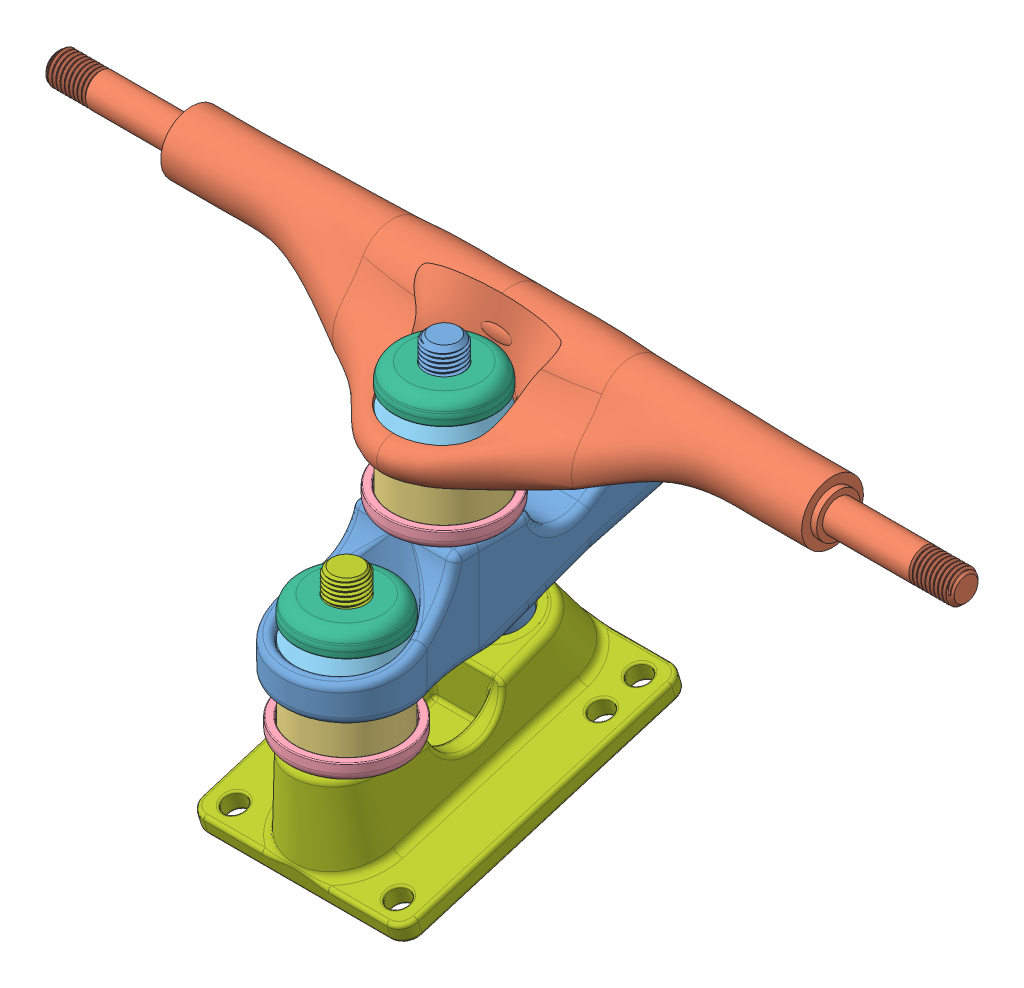
SolidWorks assembly sidewinder2_and_wheels_assembly, configuration Default. Lengths in mm.
Overall size (228 105.1 109.02).
13 component instances, 8 part files, 23 mates.
Components (placement in the parent):
- rocker-1: rocker [Default] at (-7.4415 -24.5069 31.8829) size (32.42 73.55 94.86)
- hanger_assembly-1: hanger_assembly [Default] at (-7.4415 30.4931 -9.6262) size (228 45.83 61.52)
  - hanger_uncut-1: hanger_uncut [Default] at origin size (228 45.83 61.52)
  - cutout1-1: cutout1 [Default] at (0 -14 17.0091) size (40.43 24.01 29.37) (hidden)
- cylinder_bushing-1: cylinder_bushing [Default] at (-7.4415 2.4931 7.3829) x (0.998587 0 -0.053143) z (0.053143 0 0.998587) size (25 14 25)
- cylinder_bushing_cap-3: cylinder_bushing_cap [Default] at (-7.4415 0.4931 7.3829) size (29.5 4.5 29.5)
- conical_bushing-1: conical_bushing [Default] at (-7.4415 19.4931 7.3829) size (25 10 25)
- conical_bushing_cap-1: conical_bushing_cap [Default] at (-7.4415 27.2431 7.3829) size (25.11 5.42 25.11)
- base_plate-1: base_plate [Default] at (-7.4415 -54.1328 7.9267) x (-1 0 0) z (0 0.289299 -0.957239) size (54 59.15 77.23)
- cylinder_bushing-2: cylinder_bushing [Default] at (-7.4415 -35.7569 31.8829) x (0.973023 0 0.230708) z (-0.230708 0 0.973023) size (25 14 25)
- cylinder_bushing_cap-4: cylinder_bushing_cap [Default] at (-7.4415 -37.7569 31.8829) size (29.5 4.5 29.5)
- conical_bushing-2: conical_bushing [Default] at (-7.4415 -18.7569 31.8829) size (25 10 25)
- conical_bushing_cap-2: conical_bushing_cap [Default] at (-7.4415 -11.0069 31.8829) x (0.578442 0 0.815724) z (-0.815724 0 0.578442) size (25.11 5.42 25.11)
Mates (geometry in assembly coordinates):
- Concentric2: concentric aligned: circle of conical_bushing-1; circle of conical_bushing_cap-1
- Coincident1: coincident anti-aligned: circle of cylinder_bushing-1; circle of cylinder_bushing_cap-3
- Concentric3: concentric anti-aligned: circle of rocker-1; circle of cylinder_bushing_cap-3
- Coincident2: coincident anti-aligned: plane of rocker-1 through (9.3085 0.4931 -1.8671) normal (0 1 0); plane of cylinder_bushing_cap-3 through (-2.4415 0.4931 7.3829) normal (0 -1 0)
- Concentric4: concentric aligned: cylinder of rocker-1 through (-7.4415 37.4931 7.3829) axis (0 -1 0) radius 4.7; cylinder of conical_bushing-1 through (-7.4415 19.4931 7.3829) axis (0 -1 0) radius 4.75
- Coincident3: coincident anti-aligned: plane of conical_bushing-1 through (-2.6915 29.4931 7.3829) normal (0 1 0); plane of conical_bushing_cap-1 through (2.3085 29.4931 7.3829) normal (0 -1 0)
- Parallel1: parallel anti-aligned: plane of hanger_assembly-1/hanger_uncut-1 through (-7.4415 16.4931 7.3829) normal (0 -1 0); plane of cylinder_bushing-1 through (5.0409 16.4931 6.7186) normal (0 1 0)
- Coincident5: coincident anti-aligned: plane of hanger_assembly-1/hanger_uncut-1 through (-7.4415 16.4931 7.3829) normal (0 -1 0); plane of cylinder_bushing-1 through (5.0409 16.4931 6.7186) normal (0 1 0)
- Concentric5: concentric anti-aligned: cylinder of rocker-1 through (-7.4415 37.4931 7.3829) axis (0 -1 0) radius 4.7; cylinder of hanger_assembly-1/hanger_uncut-1 through (-7.4415 -6.1021 7.3829) axis (0 1 0) radius 7.75
- Coincident6: coincident anti-aligned: plane of hanger_assembly-1/hanger_uncut-1 through (-7.4415 19.4931 7.3829) normal (0 1 0); plane of conical_bushing-1 through (5.0585 19.4931 7.3829) normal (0 -1 0)
- Parallel2: parallel: line of hanger_assembly-1/hanger_uncut-1 through (106.5585 30.4931 -9.6262) axis (-1 0 0); plane of assembly
- Concentric6: concentric anti-aligned: cylinder of rocker-1 through (-7.4415 -24.5069 31.8829) axis (0 1 0) radius 7.5; cylinder of base_plate-1 through (-7.4415 -0.7569 31.8829) axis (0 -1 0) radius 4.7
- Coincident7: coincident anti-aligned: plane of cylinder_bushing-2 through (-2.8196 -35.7569 32.9787) normal (0 -1 0); plane of cylinder_bushing_cap-4 through (5.0585 -35.7569 31.8829) normal (0 1 0)
- Concentric7: concentric aligned: cylinder of cylinder_bushing-2 through (-7.4415 -35.7569 31.8829) axis (0 -1 0) radius 4.75; cylinder of cylinder_bushing_cap-4 through (-7.4415 -37.7569 31.8829) axis (0 -1 0) radius 4.75
- Coincident8: coincident anti-aligned: plane of conical_bushing-2 through (-2.6915 -8.7569 31.8829) normal (0 1 0); plane of conical_bushing_cap-2 through (-1.8016 -8.7569 39.8362) normal (0 -1 0)
- Concentric8: concentric aligned: cylinder of conical_bushing-2 through (-7.4415 -18.7569 31.8829) axis (0 -1 0) radius 4.75; cylinder of conical_bushing_cap-2 through (-7.4415 -16.0001 31.8829) axis (0 -1 0) radius 4.75
- Concentric9: concentric aligned: cylinder of base_plate-1 through (-7.4415 -0.7569 31.8829) axis (0 -1 0) radius 4.7; cylinder of conical_bushing-2 through (-7.4415 -18.7569 31.8829) axis (0 -1 0) radius 4.75
- Concentric10: concentric aligned: cylinder of base_plate-1 through (-7.4415 -0.7569 31.8829) axis (0 -1 0) radius 4.7; cylinder of cylinder_bushing-2 through (-7.4415 -35.7569 31.8829) axis (0 -1 0) radius 4.75
- Coincident9: coincident anti-aligned: plane of base_plate-1 through (19.5586 -37.7569 22.1829) normal (0 1 0); plane of cylinder_bushing_cap-4 through (-2.4415 -37.7569 31.8829) normal (0 -1 0)
- Coincident10: coincident anti-aligned: plane of rocker-1 through (-7.4415 -18.7569 31.8829) normal (0 1 0); plane of conical_bushing-2 through (5.0585 -18.7569 31.8829) normal (0 -1 0)
- Coincident11: coincident anti-aligned: plane of rocker-1 through (-7.4415 -21.7569 31.8829) normal (0 -1 0); plane of cylinder_bushing-2 through (4.7213 -21.7569 34.7667) normal (0 1 0)
- Parallel3: parallel anti-aligned: plane of base_plate-1 through (-7.4415 -54.1328 7.9267) normal (-1 0 0); plane of assembly through (0 0 0) normal (1 0 0)
- Concentric13: concentric aligned: cylinder of hanger_assembly-1/hanger_uncut-1 through (106.5585 30.4931 -9.6262) axis (-1 0 0) radius 4; cylinder of ? through (97.5254 30.4931 -9.6262) axis (-1 0 0) radius 4
